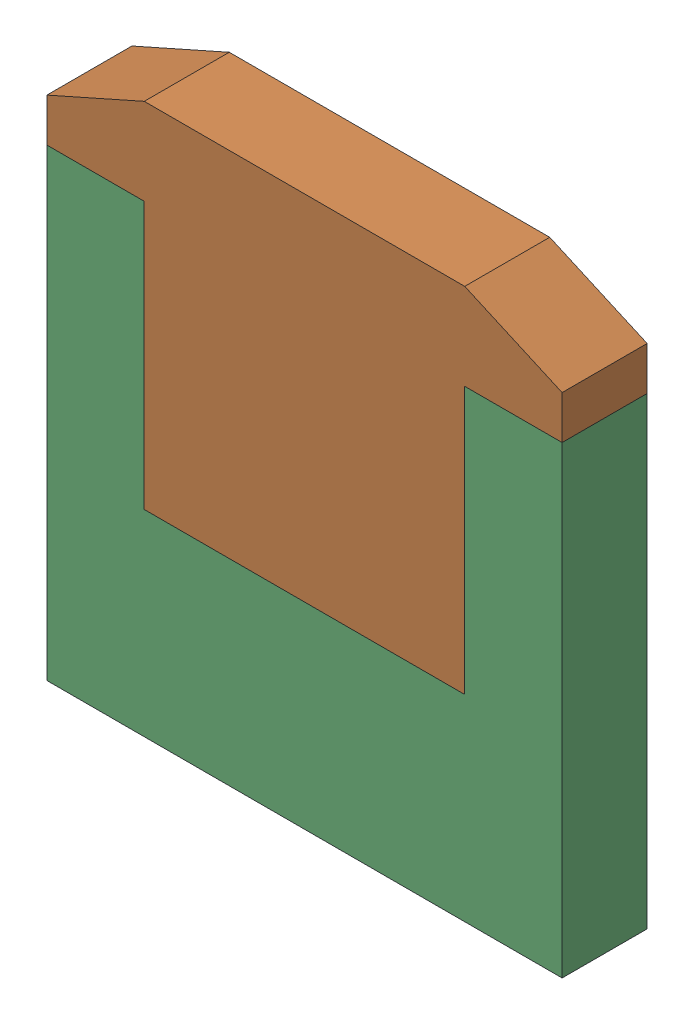
SolidWorks assembly SW3dPS-TO263-3S_BODY5, configuration Default. Lengths in mm.
Overall size (10 10.68 1.65).
6 component instances, 3 part files, 0 mates.
Components (placement in the parent):
- SW3dPS-TO263-3S_Board6-1: SW3dPS-TO263-3S_Board6 [Default] at (0 0 -0.0938) size (0.01 0.01 0.11)
- SW3dPS-TO263-3S_Free-Models9-1: SW3dPS-TO263-3S_Free-Models9 [Default] at origin size (10 10.68 1.65)
  - SW3dPS-TO263-3S_453494353-1: SW3dPS-TO263-3S_453494353 [Default] at (0 7.15 -1.6373) size (10 6.86 1.65)
    - SW3dPS-TO263-3S_Extruded15-1: SW3dPS-TO263-3S_Extruded15 [Default] at origin size (10 6.86 1.65)
  - SW3dPS-TO263-3S_453494225-1: SW3dPS-TO263-3S_453494225 [Default] at (0 4.4 -1.6373) size (10 9 1.65)
    - SW3dPS-TO263-3S_Extruded17-1: SW3dPS-TO263-3S_Extruded17 [Default] at origin size (10 9 1.65)
